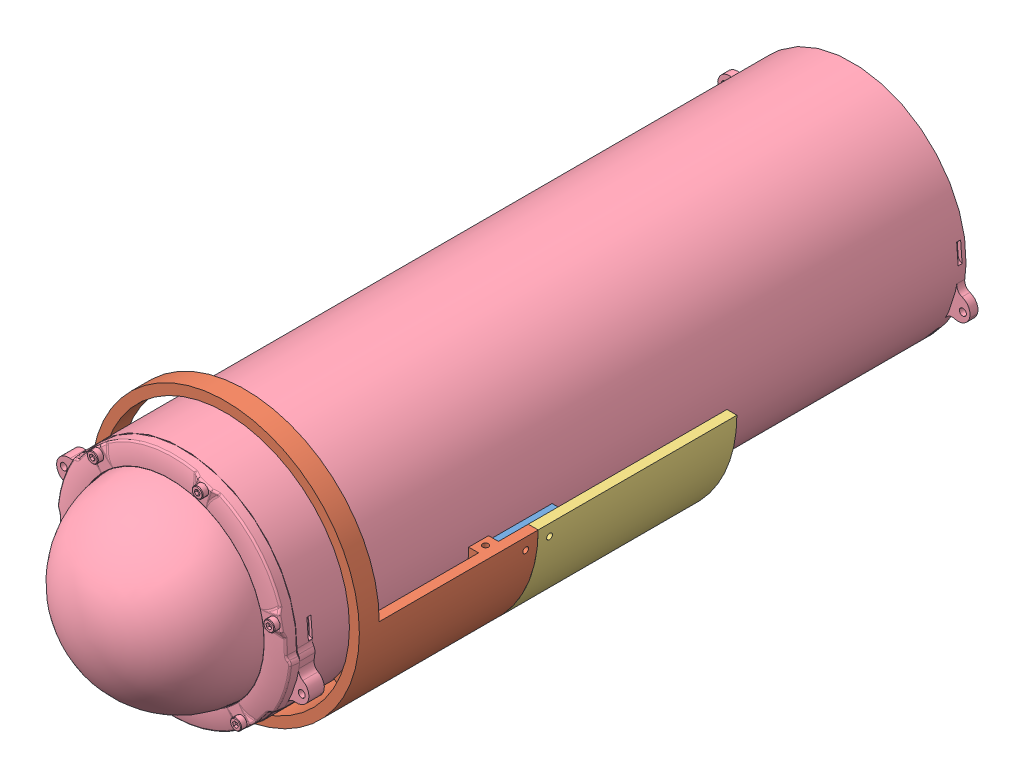
SolidWorks assembly center, configuration Default. Lengths in mm.
Overall size (164.95 159.19 386.1).
4 component instances, 4 part files, 5 mates.
Components (placement in the parent):
- center_bot_mid-1: center_bot_mid [Default] at (17.6501 103.7785 85.0679) size (125 62.5 50)
- center_bot_start-1: center_bot_start [Default] at (17.6501 103.7785 200.0679) x (-1 0 0) z (0 0 -1) size (135 135 90)
- center_bot_end-1: center_bot_end [Default] at (17.6501 103.7785 110.0679) x (-1 0 0) z (0 0 -1) size (135 67.5 100)
- P-V2-WTE-B-TS-1: P-V2-WTE-B-TS [Varsayılan] at (17.6501 103.7785 51.2084) x (-0.950484 0.310773 0) z (0 0 1) size (133 124 386.1)
Mates (geometry in assembly coordinates):
- Concentric1: concentric anti-aligned: cylinder of center_bot_middle-1 through (17.6501 103.7785 135.0679) axis (0 0 -1) radius 62.5; cylinder of center_bot_startcopy-1 through (17.6501 103.7785 190.0679) axis (0 0 1) radius 62.5
- Coincident1: coincident anti-aligned: plane of center_bot_middle-1 through (17.6501 103.7785 125.0679) normal (0 0 1); plane of center_bot_startcopy-1 through (17.6501 103.7785 125.0679) normal (0 0 -1)
- Concentric2: concentric anti-aligned: cylinder of center_bot_middle-1 through (-49.8499 97.7785 104.0679) axis (1 0 0) radius 1.5; cylinder of center_bot_end-1 through (104.1501 97.7785 104.0679) axis (-1 0 0) radius 1.5
- Concentric3: concentric anti-aligned: cylinder of center_bot_middle-1 through (17.6501 103.7785 135.0679) axis (0 0 -1) radius 62.5; cylinder of center_bot_end-1 through (17.6501 103.7785 10.0679) axis (0 0 1) radius 62.5
- Concentric4: concentric aligned: cylinder of center_bot_start-1 through (17.6501 103.7785 190.0679) axis (0 0 1) radius 62.5; cylinder of P-V2-WTE-B-TS-1 through (17.6501 103.7785 -115.2916) axis (0 0 1) radius 57.5
